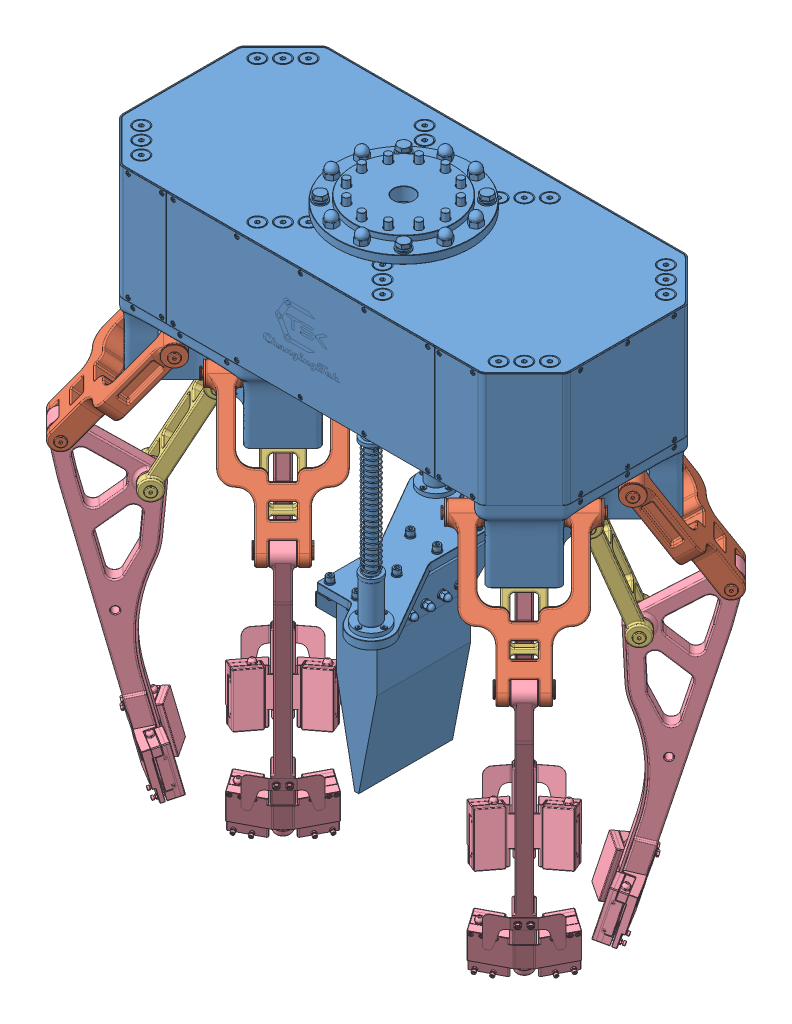
SolidWorks assembly CTHM6F460S_六指重型模块化手(有传感器), configuration 默认. Lengths in mm.
Overall size (849.2 864.95 489.2).
19 component instances, 4 part files, 57 mates.
Components (placement in the parent):
- CTM6F460.01_基座外壳组件-1: CTM6F460.01_基座外壳组件 [默认] at origin size (669.82 750.93 309.82)
- CTM6F460.02.02.01.01_驱动臂组件-1: CTM6F460.02.02.01.01_驱动臂组件 [默认] at (-260.9637 -55 80.9637) x (0.707107 0 0.707107) z (-0.480799 -0.733256 0.480799) size (175.8 43.55 219.61)
- CTM6F460.02.02.01.02_从动臂组件-1: CTM6F460.02.02.01.02_从动臂组件 [默认] at (-293.8528 -133.0624 113.8528) x (0.707107 0 0.707107) z (-0.368063 -0.853849 0.368063) size (65.8 38.07 179.78)
- CTM6F460S.02.02.01.03_手指指端组件-1: CTM6F460S.02.02.01.03_手指指端组件 [默认] at (-251.5662 -66.9163 71.5662) x (0.707107 0 0.707107) z (-0.7067 -0.033913 0.7067) size (121.01 468.06 131.51)
- CTM6F460.02.02.01.01_驱动臂组件-2: CTM6F460.02.02.01.01_驱动臂组件 [默认] at (-99.0363 -55 80.9637) x (0.707107 0 -0.707107) z (0.423968 -0.800314 0.423968) size (175.8 43.55 219.61)
- CTM6F460.02.02.01.01_驱动臂组件-4: CTM6F460.02.02.01.01_驱动臂组件 [默认] at (-260.9637 -55 -80.9637) x (-0.707107 0 0.707107) z (-0.423968 -0.800314 -0.423968) size (175.8 43.55 219.61)
- CTM6F460.02.02.01.01_驱动臂组件-6: CTM6F460.02.02.01.01_驱动臂组件 [默认] at (99.0363 -55 -80.9637) x (-0.707107 0 0.707107) z (-0.423968 -0.800314 -0.423968) size (175.8 43.55 219.61)
- CTM6F460.02.02.01.01_驱动臂组件-8: CTM6F460.02.02.01.01_驱动臂组件 [默认] at (260.9637 -55 -80.9637) x (-0.707107 0 -0.707107) z (0.423968 -0.800314 -0.423968) size (175.8 43.55 219.61)
- CTM6F460.02.02.01.01_驱动臂组件-10: CTM6F460.02.02.01.01_驱动臂组件 [默认] at (260.9637 -55 80.9637) x (0.707107 0 -0.707107) z (0.423968 -0.800314 0.423968) size (175.8 43.55 219.61)
- CTM6F460.02.02.01.02_从动臂组件-2: CTM6F460.02.02.01.02_从动臂组件 [默认] at (-66.5514 -145.4497 113.4485) x (0.707107 0 -0.707107) z (0.284028 -0.915781 0.284028) size (65.8 38.07 179.78)
- CTM6F460.02.02.01.02_从动臂组件-4: CTM6F460.02.02.01.02_从动臂组件 [默认] at (-293.4486 -145.4497 -113.4485) x (-0.707107 0 0.707107) z (-0.284028 -0.915781 -0.284028) size (65.8 38.07 179.78)
- CTM6F460.02.02.01.02_从动臂组件-6: CTM6F460.02.02.01.02_从动臂组件 [默认] at (293.4486 -145.4497 113.4485) x (0.707107 0 -0.707107) z (0.284028 -0.915781 0.284028) size (65.8 38.07 179.78)
- CTM6F460.02.02.01.02_从动臂组件-8: CTM6F460.02.02.01.02_从动臂组件 [默认] at (293.4485 -145.4497 -113.4486) x (-0.707107 0 -0.707107) z (0.284028 -0.915781 -0.284028) size (65.8 38.07 179.78)
- CTM6F460.02.02.01.02_从动臂组件-10: CTM6F460.02.02.01.02_从动臂组件 [默认] at (66.5514 -145.4497 -113.4485) x (-0.707107 0 0.707107) z (-0.284028 -0.915781 -0.284028) size (65.8 38.07 179.78)
- CTM6F460S.02.02.01.03_手指指端组件-2: CTM6F460S.02.02.01.03_手指指端组件 [默认] at (-116.3135 -73.9933 63.6865) x (0.707107 0 -0.707107) z (0.705397 -0.069504 0.705397) size (121.01 468.06 131.51)
- CTM6F460S.02.02.01.03_手指指端组件-4: CTM6F460S.02.02.01.03_手指指端组件 [默认] at (-243.6865 -73.9933 -63.6865) x (-0.707107 0 0.707107) z (-0.705397 -0.069504 -0.705397) size (121.01 468.06 131.51)
- CTM6F460S.02.02.01.03_手指指端组件-6: CTM6F460S.02.02.01.03_手指指端组件 [默认] at (243.6865 -73.9933 63.6865) x (0.707107 0 -0.707107) z (0.705397 -0.069504 0.705397) size (121.01 468.06 131.51)
- CTM6F460S.02.02.01.03_手指指端组件-8: CTM6F460S.02.02.01.03_手指指端组件 [默认] at (243.6865 -73.9933 -63.6865) x (-0.707107 0 -0.707107) z (0.705397 -0.069504 -0.705397) size (121.01 468.06 131.51)
- CTM6F460S.02.02.01.03_手指指端组件-10: CTM6F460S.02.02.01.03_手指指端组件 [默认] at (116.3135 -73.9933 -63.6865) x (-0.707107 0 0.707107) z (-0.705397 -0.069504 -0.705397) size (121.01 468.06 131.51)
Mates (geometry in assembly coordinates):
- 重合1: coincident aligned: plane of CTM6F460.01_基座外壳组件-1 through (0 0 0) normal (0 0 1); plane of assembly through (0 0 0) normal (0 0 1)
- 重合2: coincident aligned: plane of CTM6F460.01_基座外壳组件-1 through (0 0 0) normal (0 1 0); plane of assembly through (0 0 0) normal (0 1 0)
- 重合3: coincident aligned: plane of CTM6F460.01_基座外壳组件-1 through (0 0 0) normal (1 0 0); plane of assembly through (0 0 0) normal (1 0 0)
- 同心1: concentric aligned: cylinder of CTM6F460.01_基座外壳组件-1 through (-202.981 -55 138.9465) axis (0.707107 0 0.707107) radius 9; cylinder of CTM6F460.02.02.01.01_驱动臂组件-1 through (-260.9637 -55 80.9637) axis (0.707107 0 0.707107) radius 9
- 宽度1: width aligned: plane of CTM6F460.01_基座外壳组件-1 through (-231.2652 -55 110.6622) normal (0.707107 0 0.707107); plane of CTM6F460.01_基座外壳组件-1 through (-290.6622 -55 51.2652) normal (-0.707107 0 -0.707107); plane of CTM6F460.02.02.01.01_驱动臂组件-1 through (-290.6622 -55 51.2652) normal (0.707107 0 0.707107); plane of CTM6F460.02.02.01.01_驱动臂组件-1 through (-231.2652 -55 110.6622) normal (-0.707107 0 -0.707107)
- 同心2: concentric anti-aligned: cylinder of CTM6F460.01_基座外壳组件-1 through (-241.1647 -135 35.7089) axis (0.707107 0 0.707107) radius 8; cylinder of CTM6F460.02.02.01.02_从动臂组件-1 through (-207.2236 -135 69.6501) axis (-0.707107 0 -0.707107) radius 15
- 宽度2: width anti-aligned: plane of CTM6F460.02.02.01.02_从动臂组件-1 through (-224.8542 -128.8975 23.2875) normal (0.707107 0 0.707107); plane of CTM6F460.02.02.01.02_从动臂组件-1 through (-203.2875 -128.8975 44.8543) normal (-0.707107 0 -0.707107); plane of CTM6F460.01_基座外壳组件-1 through (-228.4368 -150 27.2236) normal (-0.707107 0 -0.707107); plane of CTM6F460.01_基座外壳组件-1 through (-207.2236 -150 48.4369) normal (0.707107 0 0.707107)
- 同心3: concentric aligned: cylinder of CTM6F460.02.02.01.01_驱动臂组件-1 through (-345.8552 -202.2646 165.8552) axis (0.707107 0 0.707107) radius 15; cylinder of CTM6F460S.02.02.01.03_手指指端组件-1 through (-352.9263 -202.2646 158.7842) axis (0.707107 0 0.707107) radius 15
- 同心4: concentric anti-aligned: cylinder of CTM6F460.02.02.01.02_从动臂组件-1 through (-257.4778 -267.0947 119.9043) axis (-0.707107 0 -0.707107) radius 15; cylinder of CTM6F460S.02.02.01.03_手指指端组件-1 through (-285.7621 -267.0947 91.62) axis (0.707107 0 0.707107) radius 8
- 宽度3: width anti-aligned: plane of CTM6F460.02.02.01.01_驱动臂组件-1 through (-271.7471 -55 70.1803) normal (0.707107 0 0.707107); plane of CTM6F460.02.02.01.01_驱动臂组件-1 through (-250.1803 -55 91.7471) normal (-0.707107 0 -0.707107); plane of CTM6F460S.02.02.01.03_手指指端组件-1 through (-356.4618 -202.2646 155.2486) normal (-0.707107 0 -0.707107); plane of CTM6F460S.02.02.01.03_手指指端组件-1 through (-335.2486 -202.2646 176.4618) normal (0.707107 0 0.707107)
- 同心5: concentric aligned: cylinder of CTM6F460.01_基座外壳组件-1 through (-41.0535 -55 22.981) axis (0.707107 0 -0.707107) radius 9; cylinder of CTM6F460.02.02.01.01_驱动臂组件-2 through (-99.0363 -55 80.9637) axis (0.707107 0 -0.707107) radius 9
- 宽度4: width aligned: plane of CTM6F460.01_基座外壳组件-1 through (-69.3378 -55 51.2652) normal (0.707107 0 -0.707107); plane of CTM6F460.01_基座外壳组件-1 through (-128.7348 -55 110.6622) normal (-0.707107 0 0.707107); plane of CTM6F460.02.02.01.01_驱动臂组件-2 through (-128.7348 -55 110.6622) normal (0.707107 0 -0.707107); plane of CTM6F460.02.02.01.01_驱动臂组件-2 through (-69.3378 -55 51.2652) normal (-0.707107 0 0.707107)
- 同心6: concentric aligned: cylinder of CTM6F460.01_基座外壳组件-1 through (-318.9465 -55 -22.981) axis (-0.707107 0 0.707107) radius 9; cylinder of CTM6F460.02.02.01.01_驱动臂组件-4 through (-260.9637 -55 -80.9637) axis (-0.707107 0 0.707107) radius 9
- 宽度5: width aligned: plane of CTM6F460.01_基座外壳组件-1 through (-231.2652 -55 -110.6622) normal (0.707107 0 -0.707107); plane of CTM6F460.01_基座外壳组件-1 through (-290.6622 -55 -51.2652) normal (-0.707107 0 0.707107); plane of CTM6F460.02.02.01.01_驱动臂组件-4 through (-231.2652 -55 -110.6622) normal (-0.707107 0 0.707107); plane of CTM6F460.02.02.01.01_驱动臂组件-4 through (-290.6622 -55 -51.2652) normal (0.707107 0 -0.707107)
- 同心7: concentric aligned: cylinder of CTM6F460.01_基座外壳组件-1 through (41.0535 -55 -22.981) axis (-0.707107 0 0.707107) radius 9; cylinder of CTM6F460.02.02.01.01_驱动臂组件-6 through (99.0363 -55 -80.9637) axis (-0.707107 0 0.707107) radius 9
- 宽度6: width aligned: plane of CTM6F460.01_基座外壳组件-1 through (69.3378 -55 -51.2652) normal (-0.707107 0 0.707107); plane of CTM6F460.01_基座外壳组件-1 through (128.7348 -55 -110.6622) normal (0.707107 0 -0.707107); plane of CTM6F460.02.02.01.01_驱动臂组件-6 through (128.7348 -55 -110.6622) normal (-0.707107 0 0.707107); plane of CTM6F460.02.02.01.01_驱动臂组件-6 through (69.3378 -55 -51.2652) normal (0.707107 0 -0.707107)
- 同心8: concentric aligned: cylinder of CTM6F460.01_基座外壳组件-1 through (202.981 -55 -138.9465) axis (-0.707107 0 -0.707107) radius 9; cylinder of CTM6F460.02.02.01.01_驱动臂组件-8 through (260.9637 -55 -80.9637) axis (-0.707107 0 -0.707107) radius 9
- 宽度7: width aligned: plane of CTM6F460.01_基座外壳组件-1 through (231.2652 -55 -110.6622) normal (-0.707107 0 -0.707107); plane of CTM6F460.01_基座外壳组件-1 through (290.6622 -55 -51.2652) normal (0.707107 0 0.707107); plane of CTM6F460.02.02.01.01_驱动臂组件-8 through (290.6622 -55 -51.2652) normal (-0.707107 0 -0.707107); plane of CTM6F460.02.02.01.01_驱动臂组件-8 through (231.2652 -55 -110.6622) normal (0.707107 0 0.707107)
- 同心9: concentric aligned: cylinder of CTM6F460.01_基座外壳组件-1 through (318.9465 -55 22.981) axis (0.707107 0 -0.707107) radius 9; cylinder of CTM6F460.02.02.01.01_驱动臂组件-10 through (260.9637 -55 80.9637) axis (0.707107 0 -0.707107) radius 9
- 宽度8: width aligned: plane of CTM6F460.01_基座外壳组件-1 through (231.2652 -55 110.6622) normal (-0.707107 0 0.707107); plane of CTM6F460.01_基座外壳组件-1 through (290.6622 -55 51.2652) normal (0.707107 0 -0.707107); plane of CTM6F460.02.02.01.01_驱动臂组件-10 through (231.2652 -55 110.6622) normal (0.707107 0 -0.707107); plane of CTM6F460.02.02.01.01_驱动臂组件-10 through (290.6622 -55 51.2652) normal (-0.707107 0 0.707107)
- 同心10: concentric anti-aligned: cylinder of CTM6F460.01_基座外壳组件-1 through (-144.2911 -135 61.1647) axis (0.707107 0 -0.707107) radius 8; cylinder of CTM6F460.02.02.01.02_从动臂组件-2 through (-110.3499 -135 27.2236) axis (-0.707107 0 0.707107) radius 15
- 宽度9: width anti-aligned: plane of CTM6F460.02.02.01.02_从动臂组件-2 through (-156.0065 -126.2358 45.5602) normal (0.707107 0 -0.707107); plane of CTM6F460.02.02.01.02_从动臂组件-2 through (-134.4397 -126.2358 23.9935) normal (-0.707107 0 0.707107); plane of CTM6F460.01_基座外壳组件-1 through (-131.5631 -150 27.2236) normal (0.707107 0 -0.707107); plane of CTM6F460.01_基座外壳组件-1 through (-152.7764 -150 48.4368) normal (-0.707107 0 0.707107)
- 同心11: concentric anti-aligned: cylinder of CTM6F460.01_基座外壳组件-1 through (-215.7089 -135 -61.1647) axis (-0.707107 0 0.707107) radius 8; cylinder of CTM6F460.02.02.01.02_从动臂组件-4 through (-249.6501 -135 -27.2236) axis (0.707107 0 -0.707107) radius 15
- 宽度10: width anti-aligned: plane of CTM6F460.02.02.01.02_从动臂组件-4 through (-203.9935 -126.2358 -45.5602) normal (-0.707107 0 0.707107); plane of CTM6F460.02.02.01.02_从动臂组件-4 through (-225.5603 -126.2358 -23.9935) normal (0.707107 0 -0.707107); plane of CTM6F460.01_基座外壳组件-1 through (-228.4369 -150 -27.2236) normal (-0.707107 0 0.707107); plane of CTM6F460.01_基座外壳组件-1 through (-207.2236 -150 -48.4368) normal (0.707107 0 -0.707107)
- 同心12: concentric anti-aligned: cylinder of CTM6F460.01_基座外壳组件-1 through (215.7089 -135 61.1647) axis (0.707107 0 -0.707107) radius 8; cylinder of CTM6F460.02.02.01.02_从动臂组件-6 through (249.6501 -135 27.2236) axis (-0.707107 0 0.707107) radius 15
- 宽度11: width anti-aligned: plane of CTM6F460.02.02.01.02_从动臂组件-6 through (203.9935 -126.2358 45.5602) normal (0.707107 0 -0.707107); plane of CTM6F460.02.02.01.02_从动臂组件-6 through (225.5603 -126.2358 23.9935) normal (-0.707107 0 0.707107); plane of CTM6F460.01_基座外壳组件-1 through (228.4369 -150 27.2236) normal (0.707107 0 -0.707107); plane of CTM6F460.01_基座外壳组件-1 through (207.2236 -150 48.4368) normal (-0.707107 0 0.707107)
- 同心13: concentric anti-aligned: cylinder of CTM6F460.01_基座外壳组件-1 through (241.1647 -135 -35.7089) axis (-0.707107 0 -0.707107) radius 8; cylinder of CTM6F460.02.02.01.02_从动臂组件-8 through (207.2236 -135 -69.6501) axis (0.707107 0 0.707107) radius 15
- 宽度12: width anti-aligned: plane of CTM6F460.02.02.01.02_从动臂组件-8 through (225.5602 -126.2358 -23.9935) normal (-0.707107 0 -0.707107); plane of CTM6F460.02.02.01.02_从动臂组件-8 through (203.9935 -126.2358 -45.5603) normal (0.707107 0 0.707107); plane of CTM6F460.01_基座外壳组件-1 through (207.2236 -150 -48.4369) normal (-0.707107 0 -0.707107); plane of CTM6F460.01_基座外壳组件-1 through (228.4368 -150 -27.2236) normal (0.707107 0 0.707107)
- 同心14: concentric anti-aligned: cylinder of CTM6F460.01_基座外壳组件-1 through (144.2911 -135 -61.1647) axis (-0.707107 0 0.707107) radius 8; cylinder of CTM6F460.02.02.01.02_从动臂组件-10 through (110.3499 -135 -27.2236) axis (0.707107 0 -0.707107) radius 15
- 宽度13: width anti-aligned: plane of CTM6F460.02.02.01.02_从动臂组件-10 through (156.0065 -126.2358 -45.5602) normal (-0.707107 0 0.707107); plane of CTM6F460.02.02.01.02_从动臂组件-10 through (134.4397 -126.2358 -23.9935) normal (0.707107 0 -0.707107); plane of CTM6F460.01_基座外壳组件-1 through (131.5631 -150 -27.2236) normal (-0.707107 0 0.707107); plane of CTM6F460.01_基座外壳组件-1 through (152.7764 -150 -48.4368) normal (0.707107 0 -0.707107)
- 同心15: concentric aligned: cylinder of CTM6F460.02.02.01.01_驱动臂组件-2 through (-25.4945 -214.007 154.5055) axis (0.707107 0 -0.707107) radius 15; cylinder of CTM6F460S.02.02.01.03_手指指端组件-2 through (-32.5656 -214.007 161.5765) axis (0.707107 0 -0.707107) radius 15
- 同心16: concentric anti-aligned: cylinder of CTM6F460.02.02.01.02_从动臂组件-2 through (-73.0363 -275.4115 64.5373) axis (-0.707107 0 0.707107) radius 15; cylinder of CTM6F460S.02.02.01.03_手指指端组件-2 through (-101.3206 -275.4115 92.8216) axis (0.707107 0 -0.707107) radius 8
- 宽度14: width anti-aligned: plane of CTM6F460.02.02.01.01_驱动臂组件-2 through (-88.2529 -55 70.1803) normal (-0.707107 0 0.707107); plane of CTM6F460.02.02.01.01_驱动臂组件-2 through (-109.8197 -55 91.7471) normal (0.707107 0 -0.707107); plane of CTM6F460S.02.02.01.03_手指指端组件-2 through (-36.1011 -214.007 165.1121) normal (-0.707107 0 0.707107); plane of CTM6F460S.02.02.01.03_手指指端组件-2 through (-14.8879 -214.007 143.8989) normal (0.707107 0 -0.707107)
- 同心17: concentric aligned: cylinder of CTM6F460.02.02.01.01_驱动臂组件-4 through (-334.5055 -214.007 -154.5055) axis (-0.707107 0 0.707107) radius 15; cylinder of CTM6F460S.02.02.01.03_手指指端组件-4 through (-327.4344 -214.007 -161.5765) axis (-0.707107 0 0.707107) radius 15
- 同心18: concentric anti-aligned: cylinder of CTM6F460.02.02.01.02_从动臂组件-4 through (-286.9637 -275.4115 -64.5373) axis (0.707107 0 -0.707107) radius 15; cylinder of CTM6F460S.02.02.01.03_手指指端组件-4 through (-258.6794 -275.4115 -92.8216) axis (-0.707107 0 0.707107) radius 8
- 宽度15: width anti-aligned: plane of CTM6F460.02.02.01.01_驱动臂组件-4 through (-271.7471 -55 -70.1803) normal (0.707107 0 -0.707107); plane of CTM6F460.02.02.01.01_驱动臂组件-4 through (-250.1803 -55 -91.7471) normal (-0.707107 0 0.707107); plane of CTM6F460S.02.02.01.03_手指指端组件-4 through (-323.8989 -214.007 -165.1121) normal (0.707107 0 -0.707107); plane of CTM6F460S.02.02.01.03_手指指端组件-4 through (-345.1121 -214.007 -143.8989) normal (-0.707107 0 0.707107)
- 同心19: concentric aligned: cylinder of CTM6F460.02.02.01.01_驱动臂组件-10 through (334.5055 -214.007 154.5055) axis (0.707107 0 -0.707107) radius 15; cylinder of CTM6F460S.02.02.01.03_手指指端组件-6 through (327.4344 -214.007 161.5765) axis (0.707107 0 -0.707107) radius 15
- 同心20: concentric anti-aligned: cylinder of CTM6F460.02.02.01.02_从动臂组件-6 through (286.9637 -275.4115 64.5373) axis (-0.707107 0 0.707107) radius 15; cylinder of CTM6F460S.02.02.01.03_手指指端组件-6 through (258.6794 -275.4115 92.8216) axis (0.707107 0 -0.707107) radius 8
- 宽度16: width anti-aligned: plane of CTM6F460.02.02.01.01_驱动臂组件-10 through (271.7471 -55 70.1803) normal (-0.707107 0 0.707107); plane of CTM6F460.02.02.01.01_驱动臂组件-10 through (250.1803 -55 91.7471) normal (0.707107 0 -0.707107); plane of CTM6F460S.02.02.01.03_手指指端组件-6 through (323.8989 -214.007 165.1121) normal (-0.707107 0 0.707107); plane of CTM6F460S.02.02.01.03_手指指端组件-6 through (345.1121 -214.007 143.8989) normal (0.707107 0 -0.707107)
- 同心21: concentric aligned: cylinder of CTM6F460.02.02.01.01_驱动臂组件-8 through (334.5055 -214.007 -154.5055) axis (-0.707107 0 -0.707107) radius 15; cylinder of CTM6F460S.02.02.01.03_手指指端组件-8 through (341.5765 -214.007 -147.4344) axis (-0.707107 0 -0.707107) radius 15
- 同心22: concentric anti-aligned: cylinder of CTM6F460.02.02.01.02_从动臂组件-8 through (244.5373 -275.4115 -106.9637) axis (0.707107 0 0.707107) radius 15; cylinder of CTM6F460S.02.02.01.03_手指指端组件-8 through (272.8216 -275.4115 -78.6794) axis (-0.707107 0 -0.707107) radius 8
- 宽度17: width anti-aligned: plane of CTM6F460.02.02.01.01_驱动臂组件-8 through (250.1803 -55 -91.7471) normal (0.707107 0 0.707107); plane of CTM6F460.02.02.01.01_驱动臂组件-8 through (271.7471 -55 -70.1803) normal (-0.707107 0 -0.707107); plane of CTM6F460S.02.02.01.03_手指指端组件-8 through (345.1121 -214.007 -143.8989) normal (0.707107 0 0.707107); plane of CTM6F460S.02.02.01.03_手指指端组件-8 through (323.8989 -214.007 -165.1121) normal (-0.707107 0 -0.707107)
- 同心23: concentric aligned: cylinder of CTM6F460.02.02.01.01_驱动臂组件-6 through (25.4945 -214.007 -154.5055) axis (-0.707107 0 0.707107) radius 15; cylinder of CTM6F460S.02.02.01.03_手指指端组件-10 through (32.5656 -214.007 -161.5765) axis (-0.707107 0 0.707107) radius 15
- 同心24: concentric anti-aligned: cylinder of CTM6F460.02.02.01.02_从动臂组件-10 through (73.0363 -275.4115 -64.5373) axis (0.707107 0 -0.707107) radius 15; cylinder of CTM6F460S.02.02.01.03_手指指端组件-10 through (101.3206 -275.4115 -92.8216) axis (-0.707107 0 0.707107) radius 8
- 宽度18: width anti-aligned: plane of CTM6F460.02.02.01.01_驱动臂组件-6 through (88.2529 -55 -70.1803) normal (0.707107 0 -0.707107); plane of CTM6F460.02.02.01.01_驱动臂组件-6 through (109.8197 -55 -91.7471) normal (-0.707107 0 0.707107); plane of CTM6F460S.02.02.01.03_手指指端组件-10 through (36.1011 -214.007 -165.1121) normal (0.707107 0 -0.707107); plane of CTM6F460S.02.02.01.03_手指指端组件-10 through (14.8879 -214.007 -143.8989) normal (-0.707107 0 0.707107)
- 平行1: parallel aligned: plane of CTM6F460.01_基座外壳组件-1 through (0 165 0) normal (0 1 0); plane of CTM6F460.02.02.01.01_驱动臂组件-1
- 平行2: parallel aligned: plane of CTM6F460.01_基座外壳组件-1 through (0 165 0) normal (0 1 0); plane of CTM6F460.02.02.01.01_驱动臂组件-2
- 平行3: parallel aligned: plane of CTM6F460.01_基座外壳组件-1 through (0 165 0) normal (0 1 0); plane of CTM6F460.02.02.01.01_驱动臂组件-10
- 平行4: parallel aligned: plane of CTM6F460.01_基座外壳组件-1 through (0 165 0) normal (0 1 0); plane of CTM6F460.02.02.01.01_驱动臂组件-8
- 平行5: parallel aligned: plane of CTM6F460.01_基座外壳组件-1 through (0 165 0) normal (0 1 0); plane of CTM6F460.02.02.01.01_驱动臂组件-6
- 平行6: parallel aligned: plane of CTM6F460.01_基座外壳组件-1 through (0 165 0) normal (0 1 0); plane of CTM6F460.02.02.01.01_驱动臂组件-4
- 齿轮配合2: gear = 30 : 30 mm: cylinder of CTM6F460.02.02.01.01_驱动臂组件-1 through (-260.9637 -55 80.9637) axis (0.707107 0 0.707107) radius 15; cylinder of CTM6F460.02.02.01.01_驱动臂组件-2 through (-99.0363 -55 80.9637) axis (-0.707107 0 0.707107) radius 15
- 齿轮配合3: gear = 30 : 30 mm: cylinder of CTM6F460.02.02.01.01_驱动臂组件-1 through (-260.9637 -55 80.9637) axis (-0.707107 0 -0.707107) radius 15; cylinder of CTM6F460.02.02.01.01_驱动臂组件-4 through (-260.9637 -55 -80.9637) axis (-0.707107 0 0.707107) radius 15
- 齿轮配合4: gear = 30 : 30 mm: cylinder of CTM6F460.02.02.01.01_驱动臂组件-10 through (260.9637 -55 80.9637) axis (0.707107 0 -0.707107) radius 15; cylinder of CTM6F460.02.02.01.01_驱动臂组件-8 through (260.9637 -55 -80.9637) axis (0.707107 0 0.707107) radius 15
- 齿轮配合5: gear = 30 : 30 mm: cylinder of CTM6F460.02.02.01.01_驱动臂组件-6 through (99.0363 -55 -80.9637) axis (0.707107 0 -0.707107) radius 15; cylinder of CTM6F460.02.02.01.01_驱动臂组件-8 through (260.9637 -55 -80.9637) axis (-0.707107 0 -0.707107) radius 15
- 齿轮配合6: gear = 30 : 30 mm: cylinder of CTM6F460.02.02.01.01_驱动臂组件-2 through (-99.0363 -55 80.9637) axis (-0.707107 0 0.707107) radius 15; cylinder of CTM6F460.02.02.01.01_驱动臂组件-10 through (260.9637 -55 80.9637) axis (-0.707107 0 0.707107) radius 15
- LimitAngle1: limit planar angle = 2.457633 rad anti-aligned: plane of CTM6F460.02.02.01.01_驱动臂组件-1 through (-269.1847 -45.522 89.1847) normal (-0.548062 0.631867 0.548062); plane of CTM6F460.01_基座外壳组件-1 through (-377.9142 80 45.9142) normal (-0.707107 0 0.707107)
